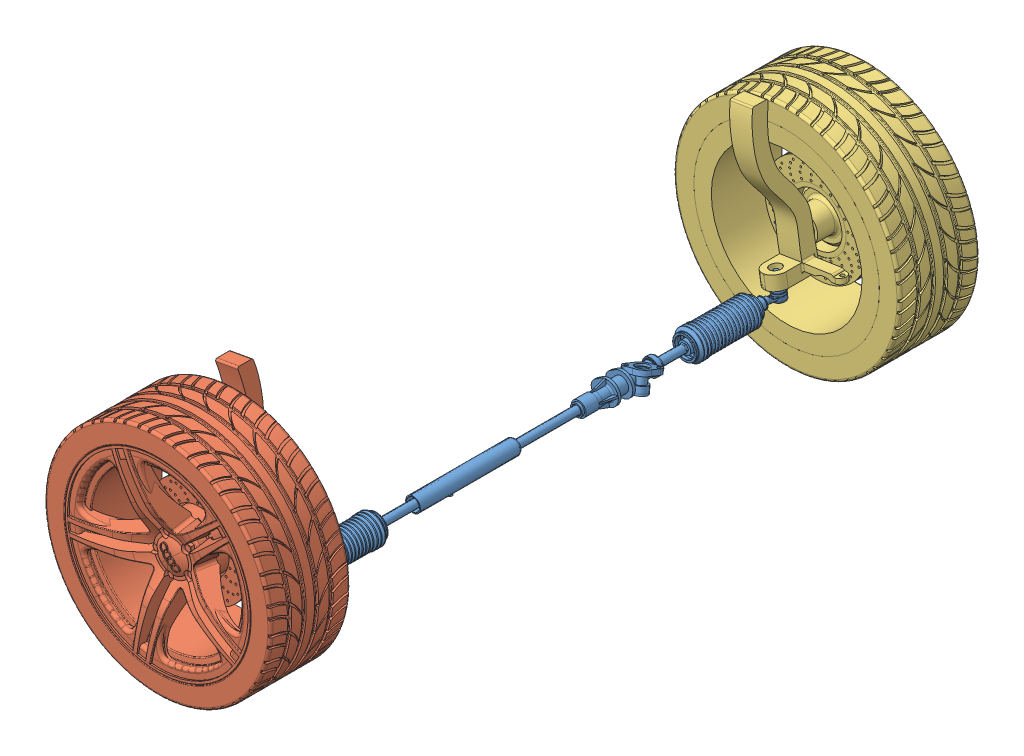
SolidWorks assembly Assem2, configuration Default. Lengths in mm.
Overall size (1083.7 1006.56 2036.97).
3 component instances, 3 part files, 4 mates.
Components (placement in the parent):
- Tie_rod_components_new-1: Tie_rod_components_new [Default] at origin size (98.29 100.41 1505.65)
- Left_wheel-1: Left_wheel [Default] at (-151.7544 70.9025 452.9041) x (-0.687698 0.725997 0) z (0.725997 0.687698 0) size (668.92 361.62 668.92)
- right_wheel-1: right_wheel [Default] at (-18.4309 114.318 -329.74) x (0 0 -1) z (-0.987251 -0.159169 0) size (361.62 859.68 828.84)
Mates (geometry in assembly coordinates):
- Concentric1: concentric: cylinder of Tie_rod_components_new-1 through (-2.9132 17.0553 1183.1535) axis (0.168368 -0.985724 0) radius 6.4528; cylinder of Left_wheel-1 through (-1.0752 6.2949 1183.1535) axis (-0.168368 0.985724 0) radius 6
- Coincident1: coincident anti-aligned: plane of Tie_rod_components_new-1 through (-10.2932 21.9368 1183.1535) normal (-0.168368 0.985724 0); plane of Left_wheel-1 through (4.9758 24.5448 1199.9035) normal (0.168368 -0.985724 0)
- Concentric2: concentric: cylinder of Tie_rod_components_new-1 through (-2.754 17.0817 -284.998) axis (0.159169 -0.987251 0) radius 6.4528; cylinder of right_wheel-1 through (3.8232 -23.7133 -284.998) axis (-0.159169 0.987251 0) radius 16.75
- Coincident2: coincident aligned: circle of Tie_rod_components_new-1; plane of right_wheel-1 through (29.3553 28.3911 -338.5753) normal (0.159169 -0.987251 0)
